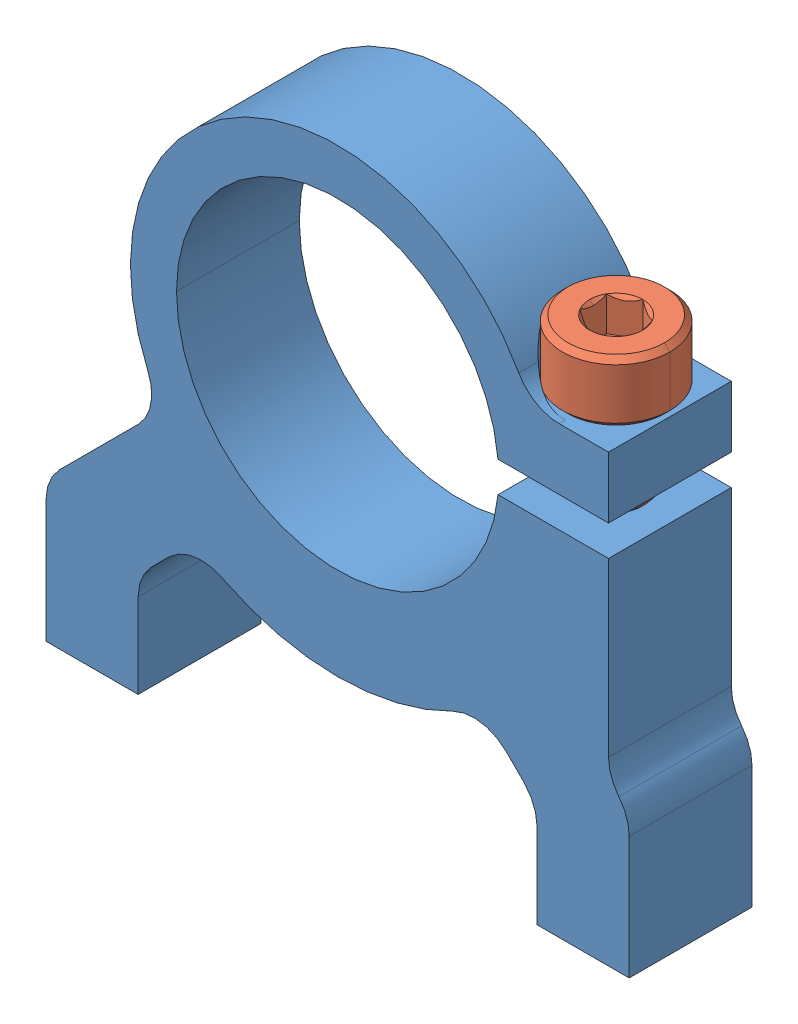
SolidWorks assembly 1-Side, 2-Post Clamping Mount (21mm Bore)1400-0032-0021, configuration Default. Lengths in mm.
Overall size (38 37.5 8).
2 component instances, 2 part files, 0 mates.
Components (placement in the parent):
- 1400-0032-0021.STEP-1: 1400-0032-0021.STEP [Default] at (5.9245 12.7459 -12.1345) size (38 37.5 8)
- 2800-0004-0010_90128A207.STEP-1: 2800-0004-0010_90128A207.STEP [Default] at (20.0767 7.7459 -8.1345) x (1 0 0) z (0 -1 0) size (7 7 14.01)
